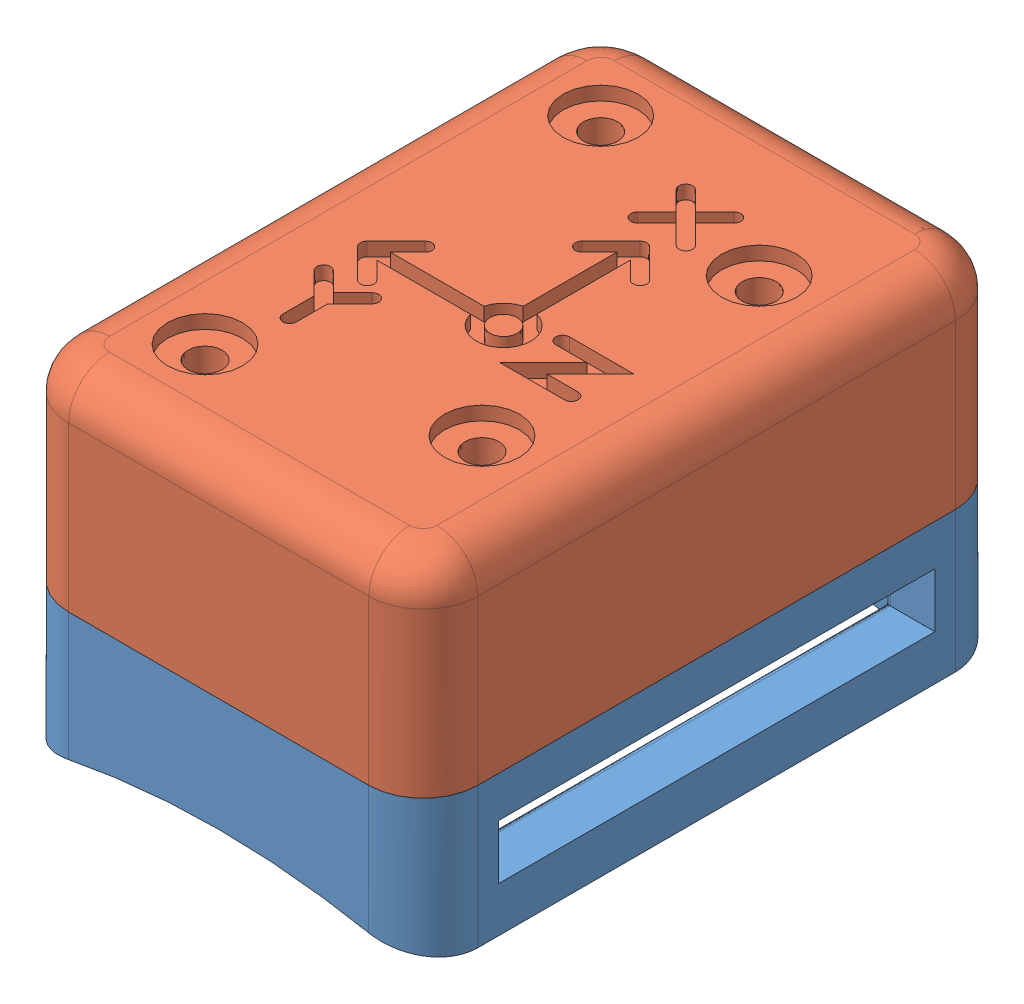
SolidWorks assembly assembly, configuration Default. Lengths in mm.
Overall size (30 25.55 43).
7 component instances, 5 part files, 14 mates.
Components (placement in the parent):
- base-1: base [Default] at (-1.272 22.5942 56.8458) size (30 15.55 43)
- cover-1: cover [Default] at (-1.272 27.5942 13.8458) x (0 0 1) z (-1 0 0) size (43 15 30)
- GY-BNO08X-1: GY-BNO08X [Default] at (8.988 29.5942 22.6458) x (1 0 0) z (0 -1 0) size (15.24 25.4 2)
- m2x10-standoff-1: m2x10-standoff [Default] at (21.688 29.5942 45.5058) size (4.5 10 3.9)
- m2x12-standoff-1: m2x12-standoff [Default] at (5.728 27.5942 20.8458) size (4.5 12 3.9)
- m2x10-standoff-2: m2x10-standoff [Default] at (21.688 29.5942 25.1858) size (4.5 10 3.9)
- m2x12-standoff-2: m2x12-standoff [Default] at (5.728 27.5942 49.8458) size (4.5 12 3.9)
Mates (geometry in assembly coordinates):
- Coincident1: coincident anti-aligned: plane of base-1 through (24.728 27.5942 17.8458) normal (0 1 0); plane of GY-BNO08X-1 through (8.988 27.5942 22.6458) normal (0 -1 0)
- Concentric1: concentric aligned: cylinder of base-1 through (21.688 17.0399 25.1858) axis (0 1 0) radius 1.25; cylinder of GY-BNO08X-1 through (21.688 27.5942 25.1858) axis (0 1 0) radius 1.25
- Concentric2: concentric aligned: cylinder of base-1 through (21.688 17.0399 45.5058) axis (0 1 0) radius 1.25; cylinder of GY-BNO08X-1 through (21.688 27.5942 45.5058) axis (0 1 0) radius 1.25
- Coincident2: coincident anti-aligned: plane of GY-BNO08X-1 through (8.988 29.5942 22.6458) normal (0 1 0); plane of m2x10-standoff-1 through (21.688 29.5942 45.5058) normal (0 -1 0)
- Concentric3: concentric anti-aligned: cylinder of GY-BNO08X-1 through (21.688 27.5942 45.5058) axis (0 1 0) radius 1.25; cylinder of m2x10-standoff-1 through (21.688 39.5942 45.5058) axis (0 -1 0) radius 1
- Coincident3: coincident anti-aligned: plane of GY-BNO08X-1 through (8.988 29.5942 22.6458) normal (0 1 0); plane of m2x10-standoff-2 through (21.688 29.5942 25.1858) normal (0 -1 0)
- Concentric4: concentric anti-aligned: cylinder of GY-BNO08X-1 through (21.688 27.5942 25.1858) axis (0 1 0) radius 1.25; cylinder of m2x10-standoff-2 through (21.688 39.5942 25.1858) axis (0 -1 0) radius 1
- Coincident4: coincident anti-aligned: plane of base-1 through (24.728 27.5942 17.8458) normal (0 1 0); plane of m2x12-standoff-2 through (5.728 27.5942 49.8458) normal (0 -1 0)
- Concentric5: concentric anti-aligned: cylinder of base-1 through (5.728 17.0399 49.8458) axis (0 1 0) radius 1.25; cylinder of m2x12-standoff-2 through (5.728 39.5942 49.8458) axis (0 -1 0) radius 1
- Coincident5: coincident anti-aligned: plane of base-1 through (24.728 27.5942 17.8458) normal (0 1 0); plane of m2x12-standoff-1 through (5.728 27.5942 20.8458) normal (0 -1 0)
- Concentric6: concentric anti-aligned: cylinder of base-1 through (5.728 17.0399 20.8458) axis (0 1 0) radius 1.25; cylinder of m2x12-standoff-1 through (5.728 39.5942 20.8458) axis (0 -1 0) radius 1
- Coincident6: coincident anti-aligned: plane of cover-1 through (24.728 39.5942 52.8458) normal (0 -1 0); plane of m2x10-standoff-2 through (21.688 39.5942 25.1858) normal (0 1 0)
- Concentric7: concentric anti-aligned: cylinder of cover-1 through (5.728 39.5942 20.8458) axis (0 1 0) radius 1.25; cylinder of m2x12-standoff-1 through (5.728 39.5942 20.8458) axis (0 -1 0) radius 1
- Concentric8: concentric aligned: circle of cover-1; cylinder of m2x10-standoff-1 through (21.688 39.5942 45.5058) axis (0 -1 0) radius 1
